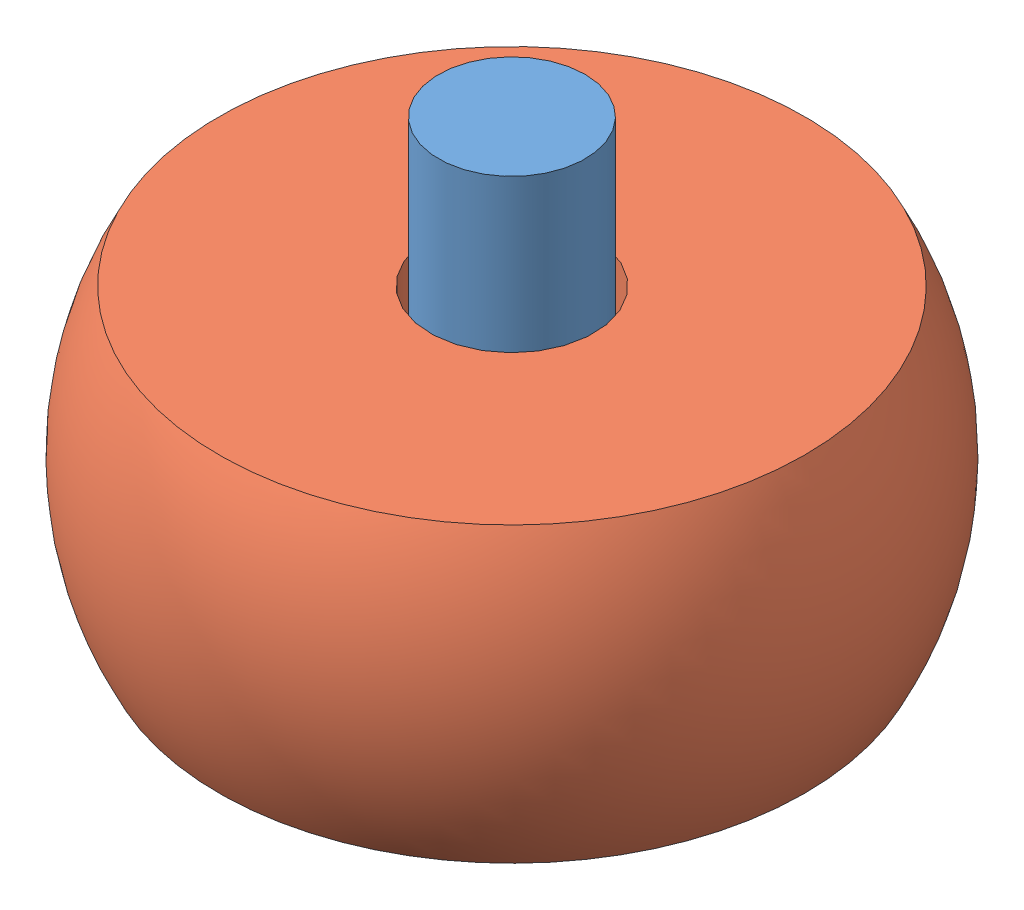
SolidWorks assembly Roller Assembly, configuration Default. Lengths in mm.
Overall size (16.81 12.7 16.81).
2 component instances, 2 part files, 2 mates.
Components (placement in the parent):
- dowel-1: dowel [Default] at origin size (3.17 12.7 3.17)
- Sleeve Bearing-1: Sleeve Bearing [Default] x (0.980576 0 0.196139) z (-0.196139 0 0.980576) size (14.29 6.35 14.29)
Mates (geometry in assembly coordinates):
- Concentric1: concentric aligned: cylinder of dowel-1 through (0 6.35 0) axis (0 -1 0) radius 1.5875; cylinder of Sleeve Bearing-1 through (0 0 0) axis (0 -1 0) radius 1.778
- Coincident1: coincident aligned: plane of Sleeve Bearing-1; plane of assembly through (0 0 0) normal (0 1 0)
